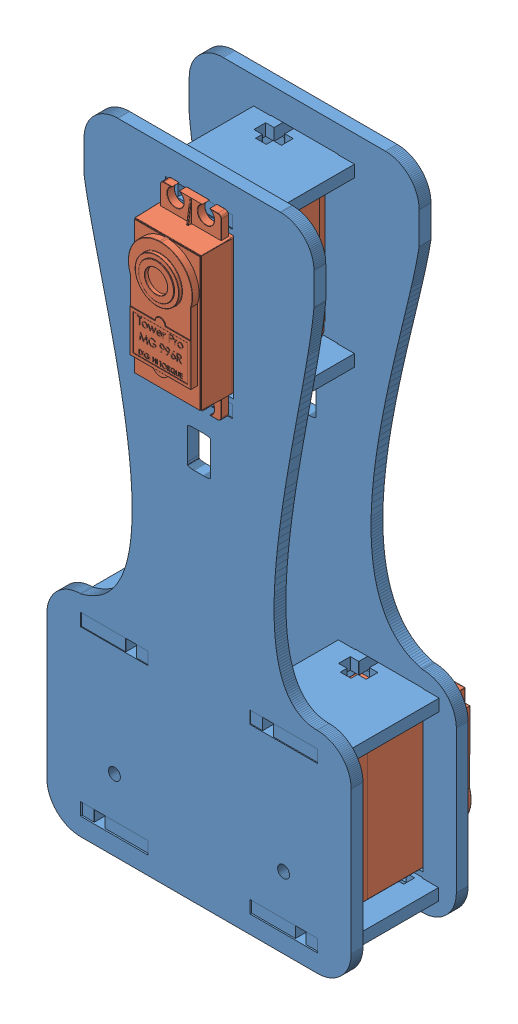
SolidWorks assembly pelvis, configuration Default. Lengths in mm.
Overall size (170.72 218.25 100).
7 component instances, 2 part files, 4 mates.
Components (placement in the parent):
- pelvisSS-1: pelvisSS [Default] at origin size (90.64 190.89 44.62)
- main_assembly-1: main_assembly [Default] at (5.6524 66.9451 58.6959) x (1 0 0.000341) z (0.000341 0 -1) size (20 53 41.5)
  - main_body-1: main_body [Default] at (15.1003 34.2066 38.7045) size (20 53 41.5)
- main_assembly-2: main_assembly [Default] at (55.7287 66.9079 58.6956) x (1 0 0.000354) z (0.000354 0 -1) size (20 53 41.5)
  - main_body-1: main_body [Default] at (15.1003 34.2066 38.7045) size (20 53 41.5)
- main_assembly-3: main_assembly [Default] at (30.2695 122.7989 -24.0878) x (1 0 -0.000016) z (0.000016 0 1) size (20 53 41.5)
  - main_body-1: main_body [Default] at (15.1003 34.2066 38.7045) size (20 53 41.5)
Mates (geometry in assembly coordinates):
- Coincident3: coincident: point of pelvisSS-1; point of assembly
- Coincident4: coincident anti-aligned: line of pelvisSS-1 through (30.7727 11.6429 0) axis (0 1 0); line of main_assembly-1/main_body-1 through (30.7727 52.4886 0) axis (0 -1 0)
- Coincident5: coincident anti-aligned: line of pelvisSS-1 through (80.8498 11.6429 0) axis (0 1 0); line of main_assembly-2/main_body-1 through (80.8498 52.4514 0) axis (0 -1 0)
- Coincident6: coincident anti-aligned: line of pelvisSS-1 through (35.3707 135.9607 34.6166) axis (0 1 0); line of main_assembly-3/main_body-1 through (35.3707 176.7554 34.6166) axis (0 -1 0)
